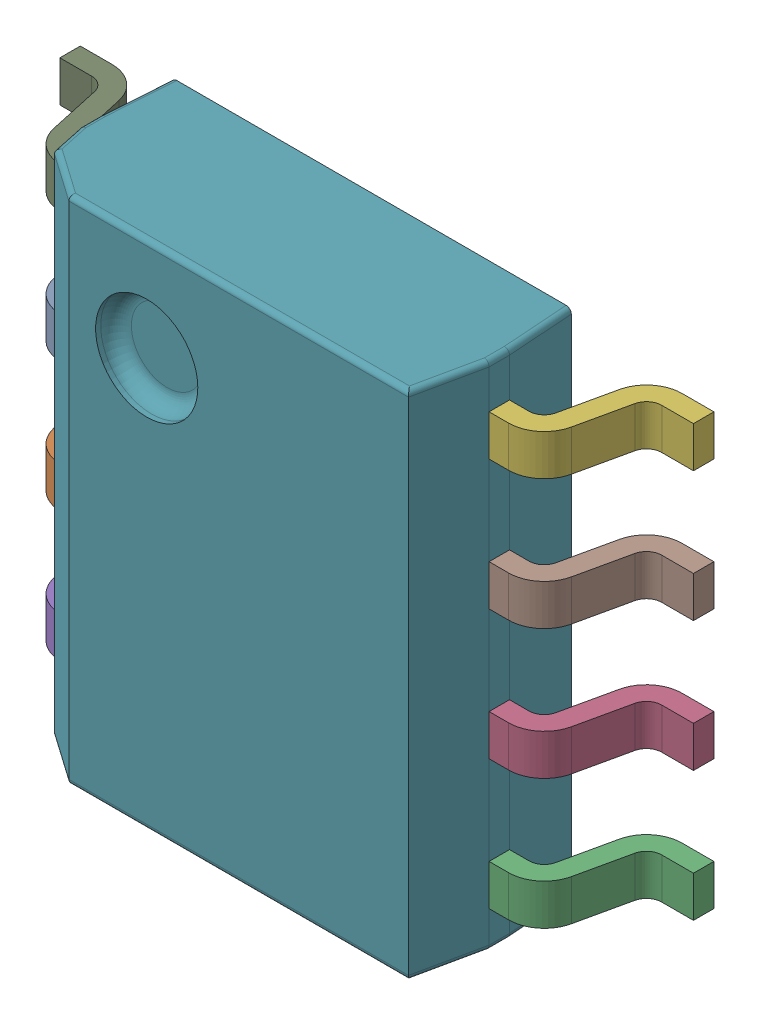
SolidWorks assembly U7, configuration Default. Lengths in mm.
Overall size (6.2 5 1.75).
10 component instances, 2 part files, 0 mates.
Components (placement in the parent):
- User_Library-SOIC-8-150-1: User_Library-SOIC-8-150 [Default] at (192.4686 56.9754 1) x (0 1 0) z (1 0 0) size (5 1.75 6.2)
  - User_Library-SOIC-8-150_pin_SOIC_SO-150_1_1-1: User_Library-SOIC-8-150_pin_SOIC_SO-150_1_1 [Default] at (0.6 0 -2) x (-1 0 0) z (0 0 -1) size (0.4 1.1 1.1)
  - User_Library-SOIC-8-150_pin_SOIC_SO-150_1_1-2: User_Library-SOIC-8-150_pin_SOIC_SO-150_1_1 [Default] at (-0.67 0 -2) x (-1 0 0) z (0 0 -1) size (0.4 1.1 1.1)
  - User_Library-SOIC-8-150_pin_SOIC_SO-150_1_1-3: User_Library-SOIC-8-150_pin_SOIC_SO-150_1_1 [Default] at (-1.94 0 2) size (0.4 1.1 1.1)
  - User_Library-SOIC-8-150_pin_SOIC_SO-150_1_1-4: User_Library-SOIC-8-150_pin_SOIC_SO-150_1_1 [Default] at (-0.67 0 2) size (0.4 1.1 1.1)
  - User_Library-SOIC-8-150_pin_SOIC_SO-150_1_1-5: User_Library-SOIC-8-150_pin_SOIC_SO-150_1_1 [Default] at (-1.94 0 -2) x (-1 0 0) z (0 0 -1) size (0.4 1.1 1.1)
  - User_Library-SOIC-8-150_pin_SOIC_SO-150_1_1-6: User_Library-SOIC-8-150_pin_SOIC_SO-150_1_1 [Default] at (1.87 0 2) size (0.4 1.1 1.1)
  - User_Library-SOIC-8-150_SOIC_150_SOIC_5X4_1_1-1: User_Library-SOIC-8-150_SOIC_150_SOIC_5X4_1_1 [Default] at origin size (5 1.5 4)
  - User_Library-SOIC-8-150_pin_SOIC_SO-150_1_1-7: User_Library-SOIC-8-150_pin_SOIC_SO-150_1_1 [Default] at (0.6 0 2) size (0.4 1.1 1.1)
  - User_Library-SOIC-8-150_pin_SOIC_SO-150_1_1-8: User_Library-SOIC-8-150_pin_SOIC_SO-150_1_1 [Default] at (1.87 0 -2) x (-1 0 0) z (0 0 -1) size (0.4 1.1 1.1)
